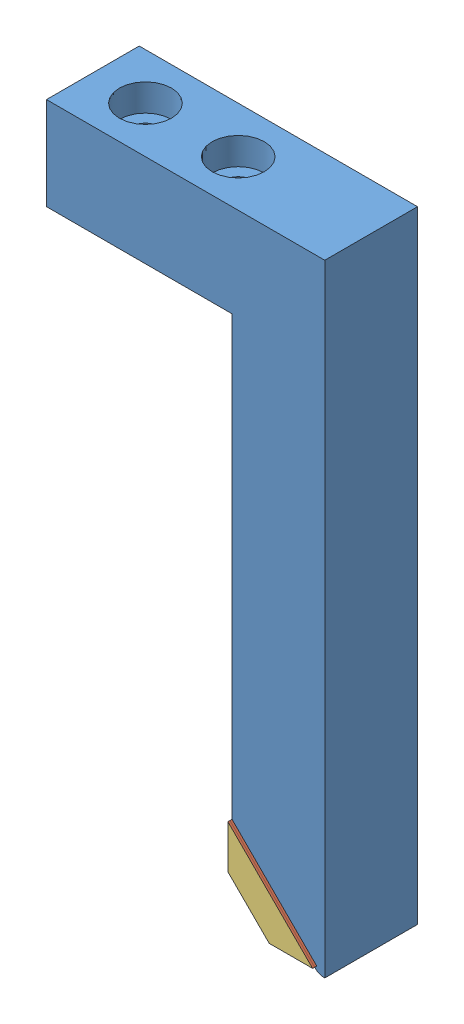
SolidWorks assembly Flat Grip Assem, configuration Default. Lengths in mm.
Overall size (38.1 86.71 12.7).
4 component instances, 3 part files, 9 mates.
Components (placement in the parent):
- Flat Grip-1: Flat Grip [Default] at (-31.0813 37.1402 -8.8313) size (38.1 86.71 12.7)
- Spacer-1: Spacer [Default] at (-0.1644 -41.5752 -8.8313) x (0 0 1) z (-0.707107 0.707107 0) size (12.7 0.4 16.41)
- Flat Grip Clamp-1: Flat Grip Clamp [Default] at (-6.2456 -47.6563 -8.8313) size (11.6 11.6 12.7)
- Spacer-2: Spacer [Default] at (-0.4473 -41.858 -8.8313) x (0 0 -1) z (0.707107 -0.707107 0) size (12.7 0.4 16.41)
Mates (geometry in assembly coordinates):
- Coincident3: coincident anti-aligned: plane of Flat Grip-1 through (5.9202 -47.0942 -15.1823) normal (-0.707107 -0.707107 0); plane of Spacer-1 through (0.1184 -41.2924 -8.8313) normal (0.707107 0.707107 0)
- Coincident4: coincident aligned: plane of Flat Grip-1 through (-31.0813 -47.9598 -2.4813) normal (0 0 1); plane of Spacer-1 through (5.9202 -47.0942 -2.4813) normal (0 0 1)
- Coincident5: coincident anti-aligned: plane of Flat Grip-1 through (5.6374 -47.377 -15.1823) normal (-0.707107 0.707107 0); plane of Spacer-1 through (5.9202 -47.0942 -15.1813) normal (0.707107 -0.707107 0)
- Coincident6: coincident anti-aligned: plane of Flat Grip Clamp-1 through (-6.2456 -36.0598 -2.4813) normal (0.707107 0.707107 0); plane of Spacer-2 through (-0.4473 -41.858 -8.8313) normal (-0.707107 -0.707107 0)
- Coincident7: coincident aligned: plane of Flat Grip Clamp-1 through (-6.2456 -47.6563 -2.4813) normal (0 0 1); plane of Spacer-2 through (-5.9663 -35.7734 -2.4813) normal (0 0 1)
- Coincident8: coincident: point of Flat Grip Clamp-1; plane of Spacer-2 through (-0.4473 -41.858 -8.8313) normal (0.707107 -0.707107 0)
- Coincident10: coincident anti-aligned: plane of Spacer-1 through (-0.1644 -41.5752 -8.8313) normal (-0.707107 -0.707107 0); plane of Spacer-2 through (-0.1644 -41.5752 -8.8313) normal (0.707107 0.707107 0)
- Coincident12: coincident aligned: plane of Flat Grip-1 through (-31.0813 -47.9598 -2.4813) normal (0 0 1); plane of Flat Grip Clamp-1 through (-6.2456 -47.6563 -2.4813) normal (0 0 1)
- Concentric1: concentric aligned: cylinder of Flat Grip-1 through (0.2773 -41.4512 -5.6563) axis (-0.707107 -0.707107 0) radius 1.1303; cylinder of Flat Grip Clamp-1 through (-3.2582 -44.9868 -5.6563) axis (-0.707107 -0.707107 0) radius 1.632
